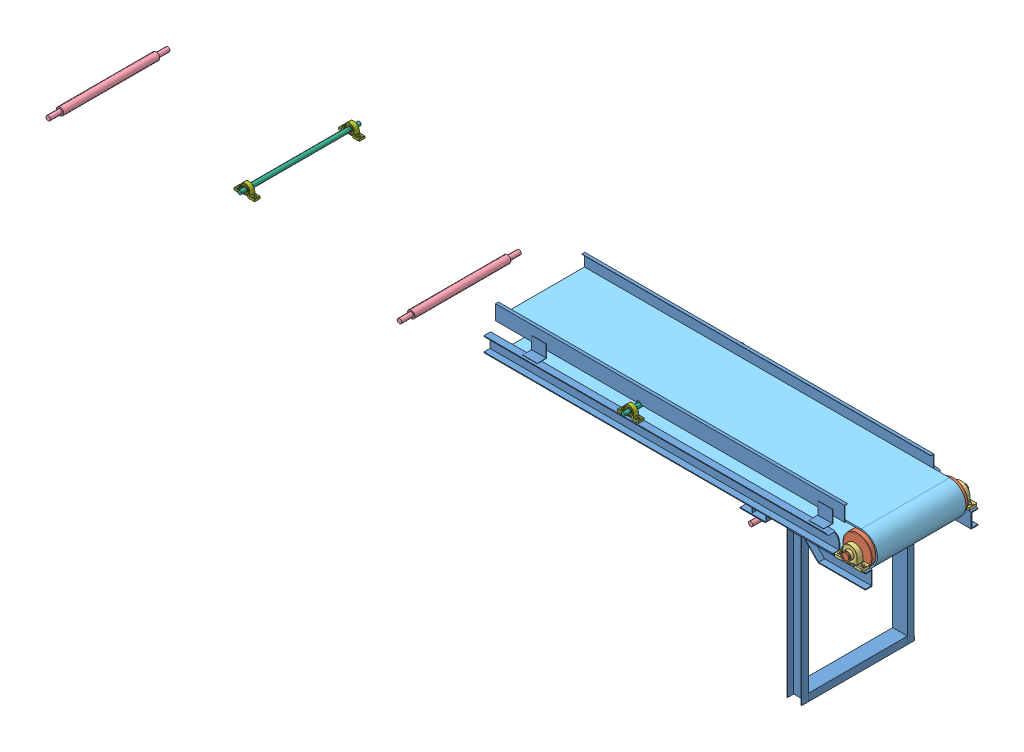
SolidWorks assembly nastrodx2, configuration Default. Lengths in mm.
Overall size (2586.13 1242.59 812.17).
18 component instances, 9 part files, 36 mates.
Components (placement in the parent):
- C-channel -b-up-2: C-channel -b-up [Default<As Machined>] at (4036.4781 3775.6231 338.4141) x (0.000207 -1 -0.000382) z (-1 -0.000206 -0.000489) size (1248 1076.8 6547.03)
- roller-belt-Motor-up-1: roller-belt-Motor-up [Default] at (7146.6561 3780.3929 4.9357) x (0.000489 0.000382 -1) z (1 0 0.000489) size (812 200 200)
- Uct 209-up-1: Uct 209-up [Default] at (956.4633 3774.9756 367.9088) x (1 0.000206 0.000489) z (-0.000489 -0.000382 1) size (144 117 54.7)
- Extender-screw-up-1: Extender-screw-up [Default] at (892.9633 3774.9625 367.8777) x (0.000489 0 -1) z (-1 -0.000206 -0.000489) size (46.02 42.15 250)
- Bearing-b_P209_45-up-1: Bearing-b_P209_45-up [Default] at (7146.4904 3726.2546 366.915) x (1 0.000206 0.000489) z (-0.000489 -0.000382 1) size (190 108 62)
- upper-roller-inside-up-1: upper-roller-inside-up [Default] at (6502.8061 3649.373 4.571) x (1 0 0.000489) z (-0.000489 -0.000382 1) size (50 50 810)
- Bearing-b_P209_45-up-2: Bearing-b_P209_45-up [Default] at (7146.8442 3726.5311 -357.0849) x (-1 -0.000206 -0.000489) z (0.000489 0.000382 -1) size (190 108 62)
- Uct 209-up-2: Uct 209-up [Default] at (956.821 3775.2551 -364.0911) x (1 0.000206 0.000489) z (0.000489 0.000382 -1) size (144 117 54.7)
- Extender-screw-up-2: Extender-screw-up [Default] at (893.321 3775.242 -364.1221) x (0.000489 0.000764 -1) z (-1 -0.000206 -0.000489) size (46.02 42.15 250)
- upper-roller-inside-up-2: upper-roller-inside-up [Default] at (4122.8064 3648.8818 3.4078) x (1 0 0.000489) z (-0.000489 -0.000382 1) size (50 50 810)
- upper-roller-inside-up-3: upper-roller-inside-up [Default] at (1742.8067 3648.3906 2.2446) x (1 0 0.000489) z (-0.000489 -0.000382 1) size (50 50 810)
- Belt^nastrodx-1: Belt^nastrodx [Default] at (4036.6418 3775.751 3.4142) x (-0.000207 1 0.000382) z (0.000489 0.000382 -1) size (224 6410.02 600) (virtual)
- roller-upper-2: roller-upper [Default] at (5639.6653 3862.5818 4.2307) x (1 0 0.000489) z (-0.000489 -0.000382 1) size (29 29 810)
- UCP-205-1: UCP-205 [Default] at (5639.4923 3862.4467 358.2306) x (0.000489 0.000382 -1) z (1 0 0.000489) size (38.7 70 140)
- UCP-205-2: UCP-205 [Default] at (5639.8383 3862.717 -349.7693) x (0.000489 0.000382 -1) z (1 0.000206 0.000489) size (38.7 70 140)
- UCP-205-3: UCP-205 [Default] at (3039.8387 3862.1804 -351.04) x (0.000489 0.000382 -1) z (1 0.000206 0.000489) size (38.7 70 140)
- UCP-205-4: UCP-205 [Default] at (3039.4927 3861.9101 356.9599) x (0.000489 0.000382 -1) z (1 0 0.000489) size (38.7 70 140)
- roller-upper-3: roller-upper [Default] at (3039.6657 3862.0453 2.9599) x (1 0 0.000489) z (-0.000489 -0.000382 1) size (29 29 810)
Mates (geometry in assembly coordinates):
- Coincident1: coincident: plane of C-channel -b-up-2 through (4036.6418 3775.751 3.4142) normal (0.000489 0.000382 -1)
- Concentric1: concentric anti-aligned: cylinder of C-channel -b-up-2 through (956.8005 3775.2391 -322.0911) axis (0.000489 0.000382 -1) radius 25; cylinder of roller-belt-Motor-up -lower-1 through (956.8425 3775.2719 -408.0911) axis (-0.000489 -0.000382 1) radius 22.5
- Width1: width anti-aligned: plane of C-channel -b-up-2 through (1036.7956 3825.2598 -333.0329) normal (-0.000489 -0.000382 1); plane of C-channel -b-up-2 through (1036.4681 3825.004 336.967) normal (0.000489 0.000382 -1); plane of roller-belt-Motor-up -lower-1 through (956.801 3775.2395 -323.0911) normal (0.000489 0.000382 -1); plane of roller-belt-Motor-up -lower-1 through (956.4834 3774.9913 326.9088) normal (-0.000489 -0.000382 1)
- Concentric2: concentric anti-aligned: cylinder of roller-belt-Motor-up -lower-1 through (956.8425 3775.2719 -408.0911) axis (-0.000489 -0.000382 1) radius 22.5; cylinder of Uct 209-up-1 through (956.4486 3774.9641 398.1088) axis (0.000489 0.000382 -1) radius 22.5
- Coincident2: coincident anti-aligned: plane of C-channel -b-up-2 through (810.446 3839.9425 375.8622) normal (-0.000489 -0.000382 1); plane of Uct 209-up-1 through (1005.9473 3833.4828 375.9553) normal (0.000489 0.000382 -1)
- Parallel1: parallel anti-aligned: plane of C-channel -b-up-2 through (810.4487 3826.9425 375.8573) normal (0.000207 -1 -0.000382); plane of Uct 209-up-1 through (1005.9567 3825.9889 359.9524) normal (-0.000207 1 0.000382)
- Concentric3: concentric aligned: cylinder of Uct 209-up-1 through (869.4634 3774.9577 367.8663) axis (1 0.000206 0.000489) radius 14.5; cylinder of Extender-screw-up-1 through (652.4634 3774.9129 367.7602) axis (1 0.000206 0.000489) radius 14.5
- Coincident3: coincident anti-aligned: plane of Uct 209-up-1 through (885.4696 3793.2991 347.3811) normal (1 0.000206 0.000489); plane of Extender-screw-up-1 through (885.4633 3774.961 367.8741) normal (-1 -0.000206 -0.000489)
- Coincident4: coincident anti-aligned: plane of C-channel -b-up-2 through (6936.5192 3726.2216 339.8124) normal (-0.000207 1 0.000382); plane of Bearing-b_P209_45-up-1 through (7051.4772 3726.2247 393.8686) normal (0.000207 -1 -0.000382)
- Coincident5: coincident aligned: plane of C-channel -b-up-2 through (4036.4781 3775.6231 338.4141) normal (0.000489 0.000382 -1); plane of Bearing-b_P209_45-up-1 through (7146.5036 3726.265 339.915) normal (0.000489 0.000382 -1)
- Concentric4: concentric aligned: cylinder of Bearing-b_P209_45-up-1 through (7146.5193 3780.286 284.9356) axis (-0.000489 -0.000382 1) radius 22.5; cylinder of roller-belt-Motor-up-1 through (7146.8545 3780.5479 -401.0642) axis (-0.000489 -0.000382 1) radius 22.5
- Coincident6: coincident anti-aligned: plane of C-channel -b-up-2 through (-723.5039 3690.6538 336.0556) normal (0.000207 -1 -0.000382); plane of UCP206-3 through (1710.6085 3691.1361 389.7453) normal (-0.000207 1 0.000382)
- Width4: width aligned: plane of C-channel -b-up-2 through (1657.6337 3691.1448 338.2194) normal (-1 -0.000206 -0.000489); plane of C-channel -b-up-2 through (1827.6337 3691.1799 338.3025) normal (1 0.000206 0.000489); plane of UCP206-3 through (1660.11 3691.1268 386.7206) normal (-1 -0.000206 -0.000489); plane of UCP206-3 through (1825.1305 3691.1769 344.8013) normal (1 0.000206 0.000489)
- Width5: width anti-aligned: plane of UCP206-3 through (1777.632 3691.1682 341.7781) normal (0.000489 0.000382 -1); plane of UCP206-3 through (1822.1085 3691.1591 389.7998) normal (-0.000489 -0.000382 1); plane of C-channel -b-up-2 through (1827.6068 3691.1589 393.3025) normal (-0.000489 -0.000382 1); plane of C-channel -b-up-2 through (1827.6337 3691.1799 338.3025) normal (0.000489 0.000382 -1)
- Coincident8: coincident anti-aligned: plane of C-channel -b-up-2 through (1656.4957 3691.145 337.2188) normal (0.000207 -1 -0.000382); plane of UCP206-1 through (4090.6082 3691.6273 390.9085) normal (-0.000207 1 0.000382)
- Width6: width anti-aligned: plane of UCP206-1 through (4040.1097 3691.618 387.8838) normal (-1 -0.000206 -0.000489); plane of UCP206-1 through (4205.1302 3691.6681 345.9645) normal (1 0.000206 0.000489); plane of C-channel -b-up-2 through (4207.6333 3691.6711 339.4657) normal (1 0.000206 0.000489); plane of C-channel -b-up-2 through (4037.6334 3691.636 339.3826) normal (-1 -0.000206 -0.000489)
- Width7: width anti-aligned: plane of UCP206-1 through (4087.6082 3691.6266 390.907) normal (-0.000489 -0.000382 1); plane of UCP206-1 through (4043.1316 3691.6358 342.8853) normal (0.000489 0.000382 -1); plane of C-channel -b-up-2 through (4207.6333 3691.6711 339.4657) normal (0.000489 0.000382 -1); plane of C-channel -b-up-2 through (4207.6065 3691.6501 394.4657) normal (-0.000489 -0.000382 1)
- Coincident9: coincident anti-aligned: plane of C-channel -b-up-2 through (4036.4954 3691.6361 338.3821) normal (0.000207 -1 -0.000382); plane of UCP206-2 through (6470.6078 3692.1184 392.0717) normal (-0.000207 1 0.000382)
- Width8: width anti-aligned: plane of C-channel -b-up-2 through (6587.6061 3692.1412 395.6289) normal (-0.000489 -0.000382 1); plane of C-channel -b-up-2 through (6587.633 3692.1622 340.6289) normal (0.000489 0.000382 -1); plane of UCP206-2 through (6423.1313 3692.127 344.0485) normal (0.000489 0.000382 -1); plane of UCP206-2 through (6467.6078 3692.1178 392.0702) normal (-0.000489 -0.000382 1)
- Width9: width anti-aligned: plane of C-channel -b-up-2 through (6417.633 3692.1272 340.5458) normal (-1 -0.000206 -0.000489); plane of C-channel -b-up-2 through (6587.633 3692.1622 340.6289) normal (1 0.000206 0.000489); plane of UCP206-2 through (6585.1298 3692.1592 347.1277) normal (1 0.000206 0.000489); plane of UCP206-2 through (6420.1093 3692.1092 389.047) normal (-1 -0.000206 -0.000489)
- Concentric5: concentric anti-aligned: cylinder of upper-roller-inside-up-1 through (6502.6082 3649.2184 409.571) axis (0.000489 0.000382 -1) radius 15; cylinder of UCP206-2 through (6502.6358 3649.24 352.933) axis (-0.000489 -0.000382 1) radius 15
- Concentric6: concentric anti-aligned: cylinder of UCP206-1 through (4122.6362 3648.7488 351.7698) axis (-0.000489 -0.000382 1) radius 15; cylinder of upper-roller-inside-up-2 through (4122.6085 3648.7272 408.4078) axis (0.000489 0.000382 -1) radius 15
- Concentric7: concentric anti-aligned: cylinder of UCP206-3 through (1742.6365 3648.2576 350.6066) axis (-0.000489 -0.000382 1) radius 15; cylinder of upper-roller-inside-up-3 through (1742.6088 3648.236 407.2446) axis (0.000489 0.000382 -1) radius 15
- Width12: width anti-aligned: plane of upper-roller-inside-up-3 through (1742.6088 3648.236 407.2446) normal (-0.000489 -0.000382 1); plane of upper-roller-inside-up-3 through (1743.0046 3648.5453 -402.7553) normal (0.000489 0.000382 -1); plane of C-channel -b-up-2 through (1036.4681 3825.004 336.967) normal (0.000489 0.000382 -1); plane of C-channel -b-up-2 through (1036.7956 3825.2598 -333.0329) normal (-0.000489 -0.000382 1)
- InPlace1: in place: plane of ? through (4036.6525 3723.6228 3.3943) normal (0.000489 0.000382 -1); plane of ? through (4036.6525 3723.6228 3.3943) normal (0.000489 0.000382 -1); moOrthogonalPlaneRef_w of ? through (4036.6525 3723.6228 3.3943) normal (0.000489 0.000382 -1); plane of ? through (4036.6525 3723.6228 3.3943) normal (1 0.000206 0.000489); plane of ? through (4036.6525 3723.6228 3.3943) normal (0.000489 0.000382 -1); plane of ? through (4036.6525 3723.6228 3.3943) normal (-0.000207 1 0.000382); plane of C-channel -b-up-2 through (4036.6418 3775.751 3.4142) normal (0.000489 0.000382 -1); unknown of Belt^nastrodx-1
- Coincident13: coincident aligned: plane of C-channel -b-up-2; plane of Belt^nastrodx-1
- Coincident14: coincident aligned: moOrthogonalPlaneRef_w of C-channel -b-up-2; plane of Belt^Assembly of conveyor-1 through (4036.6418 3775.751 3.4142) normal (1 0.000206 0.000489)
- Coincident15: coincident anti-aligned: moOrthogonalPlaneRef_w of C-channel -b-up-2; plane of Belt^Assembly of conveyor-1 through (4036.6418 3775.751 3.4142) normal (-0.000207 1 0.000382)
- Concentric11: concentric anti-aligned: cylinder of roller-upper-2 through (5639.4674 3862.4272 409.2306) axis (0.000489 0.000382 -1) radius 12.5; cylinder of UCP-205-1 through (5639.4853 3862.4412 372.5306) axis (-0.000489 -0.000382 1) radius 12.5
- Coincident24: coincident aligned: plane of C-channel -b-up-2 through (1036.4681 3825.004 336.967) normal (0.000489 0.000382 -1); plane of UCP-205-1 through (5571.1016 3838.7539 339.1881) normal (0.000489 0.000382 -1)
- Concentric12: concentric aligned: cylinder of roller-upper-2 through (5639.8632 3862.7365 -400.7693) axis (-0.000489 -0.000382 1) radius 12.5; cylinder of UCP-205-2 through (5639.8313 3862.7115 -335.4693) axis (-0.000489 -0.000382 1) radius 12.5
- Coincident25: coincident anti-aligned: plane of C-channel -b-up-2 through (1036.7956 3825.2598 -333.0329) normal (-0.000207 1 0.000382); plane of UCP-205-2 through (5709.8551 3826.2387 -368.749) normal (0.000207 -1 -0.000382)
- Coincident26: coincident aligned: plane of C-channel -b-up-2 through (1036.7956 3825.2598 -333.0329) normal (-0.000489 -0.000382 1); plane of UCP-205-2 through (5571.4339 3838.9956 -330.8117) normal (-0.000489 -0.000382 1)
- Coincident28: coincident anti-aligned: plane of roller-belt-Motor-up -lower-1 through (956.8425 3775.2719 -408.0911) normal (0.000489 0.000382 -1); plane of Gear_motor-b-up-1 through (972.9459 3759.1753 -408.0893) normal (-0.000489 -0.000382 1)
- Concentric14: concentric anti-aligned: circle of roller-belt-Motor-up -lower-1; cylinder of Gear_motor-b-up-1 through (956.8767 3775.2987 -478.0911) axis (-0.000489 -0.000382 1) radius 17.5
- Parallel2: parallel aligned: plane of C-channel -b-up-2 through (1036.8162 3725.2598 -333.0711) normal (0.000207 -1 -0.000382); plane of Gear_motor-b-up-1 through (1248.8044 3664.8321 -669.7906) normal (0.000207 -1 -0.000382)
